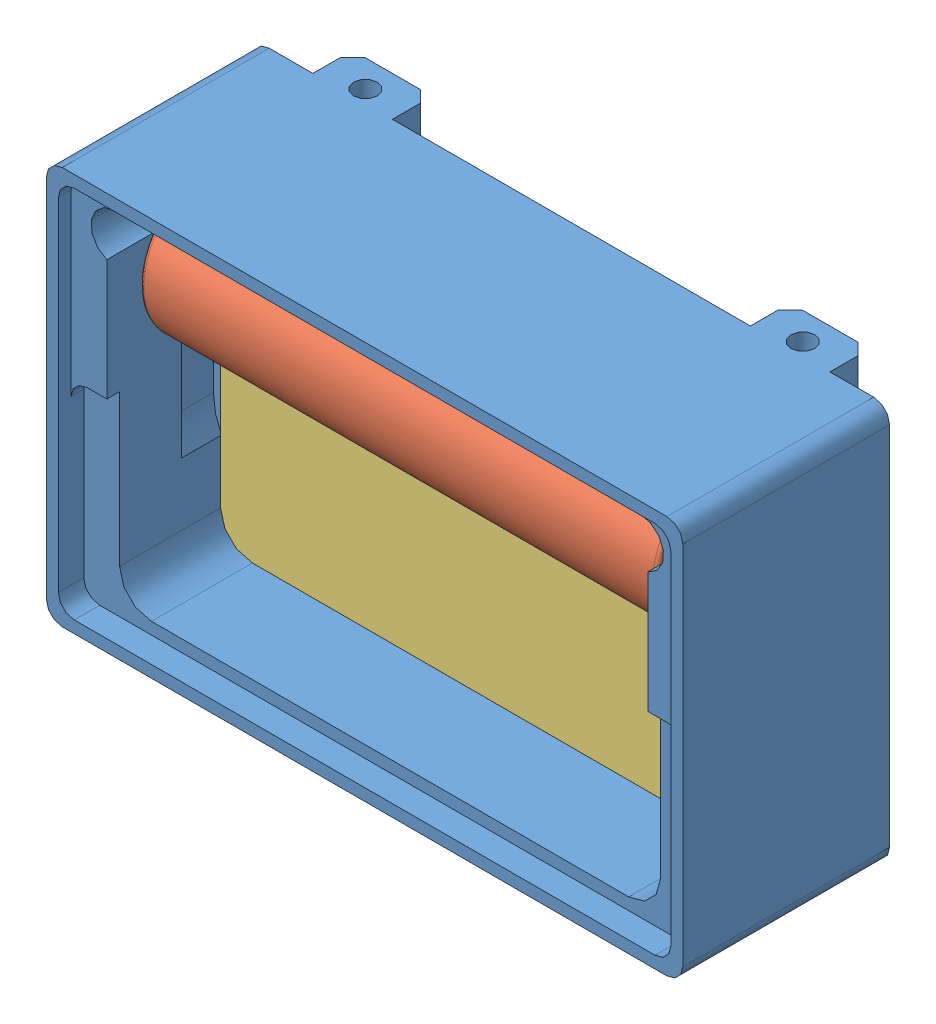
SolidWorks assembly device, configuration По умолчанию. Lengths in mm.
Overall size (80 58.83 58.83).
3 component instances, 3 part files, 5 mates.
Components (placement in the parent):
- korpus-1: korpus [По умолчанию] at origin size (80 58.83 58.83)
- Battery-1: Battery [По умолчанию] at (32.6187 13 12.864) x (0 0.820776 0.571251) z (-1 0 0) size (18 18 65)
- PCB-1: PCB [По умолчанию] at (0 -9.5 8.5) size (68 25 1.6)
Mates (geometry in assembly coordinates):
- Касательность2: tangent anti-aligned: plane of korpus-1 through (-33 22 -84.3801) normal (0 -1 0); cylinder of Battery-1 through (-32.3813 13 12.864) axis (1 0 0) radius 9
- Совпадение1: coincident anti-aligned: plane of korpus-1 through (-34 13.5091 -84.3801) normal (1 0 0); plane of PCB-1 through (-34 -18 10.1) normal (-1 0 0)
- Совпадение2: coincident anti-aligned: plane of korpus-1 through (-30 -18 8.5) normal (0 0 1); plane of PCB-1 through (-30 -18 8.5) normal (0 0 -1)
- Совпадение3: coincident anti-aligned: plane of korpus-1 through (-30 -22 -84.3801) normal (0 1 0); plane of PCB-1 through (-30 -22 10.1) normal (0 -1 0)
- Tangent1: tangent anti-aligned: plane of korpus-1 through (25.5 6.136 7) normal (0 0.707107 0.707107); cylinder of Battery-1 through (-32.3813 13 12.864) axis (1 0 0) radius 9
